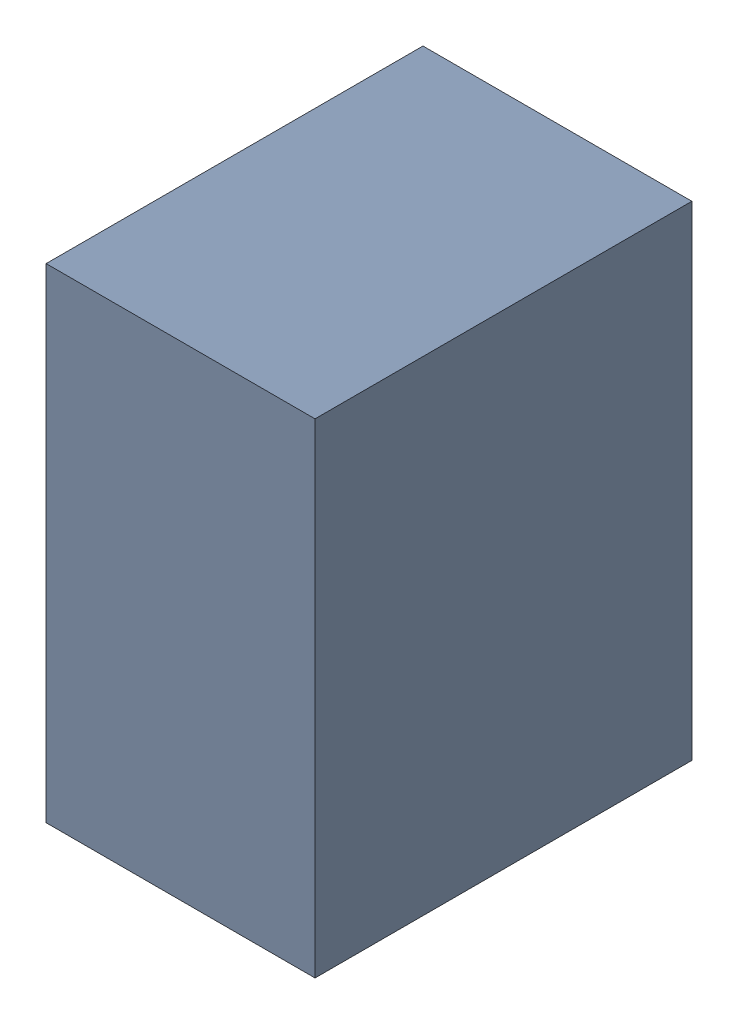
SolidWorks assembly C35, configuration Default. Lengths in mm.
Overall size (1 1.8 1.4).
3 component instances, 2 part files, 0 mates.
Components (placement in the parent):
- 1088883208-1: 1088883208 [Default] at (10.45 29.2 -3.044) size (1 1.8 1.4)
  - Extruded-45-1: Extruded-45 [Default] at origin size (1 1.8 1.4)
- C0603-1: C0603 [Default] at (10.8501 30 -1.644) x (0 -1 0) z (1 0 0) size (1.6 0.5 0.8)
